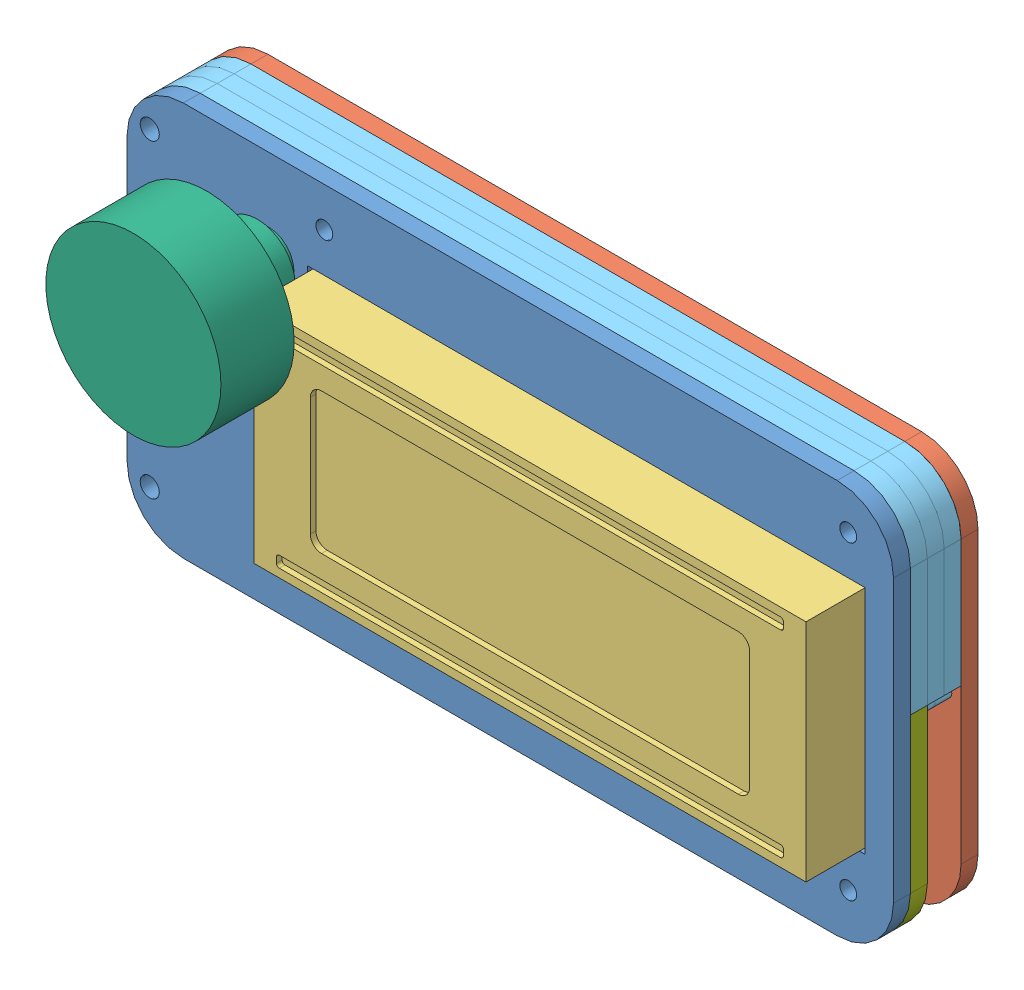
SolidWorks assembly Panel1, configuration Default. Lengths in mm.
Overall size (141.06 81.37 39).
9 component instances, 7 part files, 24 mates.
Components (placement in the parent):
- Panel-1: Panel [Default] at (36.5683 121.8199 -7) x (-1 0 0) z (0 -1 0) size (136.06 3 70)
- Panel back-1: Panel back [Default] at (36.5683 121.8199 -19) x (-1 0 0) z (0 0 -1) size (136.06 70 3)
- lcd-1: lcd [Default] at (-38 75.2988 -17) x (1 0 0) z (0 -1 0) size (98 15 60)
- Part2^Panel-1: Part2^Panel [Default] at (94.6769 215.7132 -12) x (-1 0 0) z (0 0 -1) size (128.47 69.61 8)
- Part1^Panel2-1: Part1^Panel2 [Default] at (0 0 -10) x (-1 0 0) z (0 0 -1) size (136.06 35.69 3)
- Part1^Panel2-2: Part1^Panel2 [Default] at (0 0 -13) x (-1 0 0) z (0 0 -1) size (136.06 35.69 3)
- Part1^Panel2-3: Part1^Panel2 [Default] at (0 0 -16) x (-1 0 0) z (0 0 -1) size (136.06 35.69 3)
- Part3^Panel1-2: Part3^Panel1 [Default] at (0 0 -12) size (31.09 31.09 29) (virtual)
- Part1^Pane3-1: Part1^Pane3 [Default] at (0 0 -10) x (-1 0 0) z (0 0 -1) size (141.06 81.37 3)
Mates (geometry in assembly coordinates):
- Coincidente1: coincident anti-aligned: plane of Panel-1 through (58.1909 88.3774 85.8438) normal (0 1 0); plane of lcd-1 through (-3.2409 88.3774 128.3649) normal (0 -1 0)
- Concêntrico5: concentric: cylinder of Panel-1 through (95.5 136.7988 -10) axis (0 0 1) radius 1.5; cylinder of Panel back-1 through (95.5 136.7988 -22) axis (0 0 1) radius 1.3
- Concentric4: concentric: circle of Panel-1; circle of lcd-1
- Concentric5: concentric: circle of Panel-1; circle of lcd-1
- Coincident9: coincident: plane of Panel-1 through (36.5683 121.8199 -10) normal (0 0 -1); plane of lcd-1 through (98 79.2988 -10) normal (0 0 1)
- Concentric6: concentric: cylinder of Panel back-1 through (2.5 136.7988 -22) axis (0 0 1) radius 1.5; cylinder of lcd-1 through (2.5 136.7988 -10) axis (0 0 -1) radius 1.75
- Coincident10: coincident: plane of Panel-1 through (36.5683 121.8199 -10) normal (0 0 -1); plane of Part1^Panel2-1 through (93.5366 83.7988 -10) normal (0 0 1)
- Concentric7: concentric: cylinder of Panel-1 through (-22.5267 133.7988 -10) axis (0 0 1) radius 10; cylinder of Part1^Panel2-1 through (-22.5267 133.7988 -13) axis (0 0 1) radius 10
- Coincident12: coincident: plane of lcd-1 through (98 139.2988 -10) normal (1 0 0); plane of Part2^Panel-1 through (98 215.7132 -15) normal (1 0 0)
- Coincident13: coincident: plane of lcd-1 through (98 79.2988 -12) normal (0 0 -1); plane of Part2^Panel-1 through (94.6769 215.7132 -12) normal (0 0 1)
- Coincident14: coincident: plane of lcd-1 through (98 79.2988 -10) normal (0 -1 0); plane of Part2^Panel-1 through (94.6769 79.2988 -15) normal (0 -1 0)
- Parallel1: parallel: plane of lcd-1 through (98 79.2988 -10) normal (0 -1 0); plane of ? through (98 79.1138 -13) normal (0 1 0)
- Coincident16: coincident: plane of ? through (93.5366 83.7988 -13) normal (0 0 -1); plane of Part1^Panel2-2 through (93.5366 83.7988 -13) normal (0 0 1)
- Concentric8: concentric: cylinder of Panel-1 through (-22.5267 133.7988 -10) axis (0 0 1) radius 10; cylinder of Part1^Panel2-2 through (-22.5267 133.7988 -16) axis (0 0 1) radius 10
- Parallel2: parallel: plane of lcd-1 through (98 79.2988 -10) normal (0 -1 0); plane of Part1^Panel2-2 through (98 79.1138 -16) normal (0 1 0)
- Coincident17: coincident: plane of Part1^Panel2-2 through (93.5366 83.7988 -16) normal (0 0 -1); plane of Part1^Panel2-3 through (93.5366 83.7988 -16) normal (0 0 1); plane of ?; cylinder of ?; cylinder of ?; cylinder of ?; plane of Part1^Panel2-3
- Concentric9: concentric: cylinder of Panel-1 through (-22.5267 133.7988 -10) axis (0 0 1) radius 10; cylinder of Part1^Panel2-3 through (-22.5267 133.7988 -19) axis (0 0 1) radius 10
- Parallel3: parallel: plane of lcd-1 through (98 79.2988 -10) normal (0 -1 0); plane of Part1^Panel2-3 through (98 79.1138 -19) normal (0 1 0)
- Coincident18: coincident: plane of Panel back-1 through (103.5366 133.7988 -22) normal (1 0 0); plane of Part1^Panel2-3 through (103.5366 133.7988 -19) normal (1 0 0)
- Coincident19: coincident: plane of Panel back-1 through (-22.5267 133.7988 -19) normal (0 0 1); plane of Part1^Panel2-3 through (93.5366 83.7988 -19) normal (0 0 -1); cylinder of ?; cylinder of ?; cylinder of Part1^Pane3-1; cylinder of ?; cylinder of ?; cylinder of Part1^Panel2-1; cylinder of ?; cylinder of ?; cylinder of Part1^Pane3-1; cylinder of ?; cylinder of ?; cylinder of ?
- Concentric10: concentric: cylinder of Part1^Panel2-1 through (100.7855 109.2063 -3) axis (0 0 -1) radius 1.1001; cylinder of Part1^Pane3-1 through (100.7855 109.2063 -3) axis (0 0 -1) radius 1.1001
- Concentric11: concentric: cylinder of Part1^Panel2-1 through (-28.6722 125.6963 -3) axis (0 0 -1) radius 1.2952; cylinder of Part1^Pane3-1 through (-28.6722 125.6963 -3) axis (0 0 -1) radius 1.2952
- Coincident20: coincident: plane of ? through (93.5366 83.7988 -10) normal (0 0 1); plane of ? through (93.5366 83.7988 -10) normal (0 0 1)
- Coincident21: coincident: plane of Panel back-1 through (-32.5267 133.7988 -22) normal (-1 0 0); plane of ? through (-32.5267 83.7988 -13) normal (-1 0 0)
